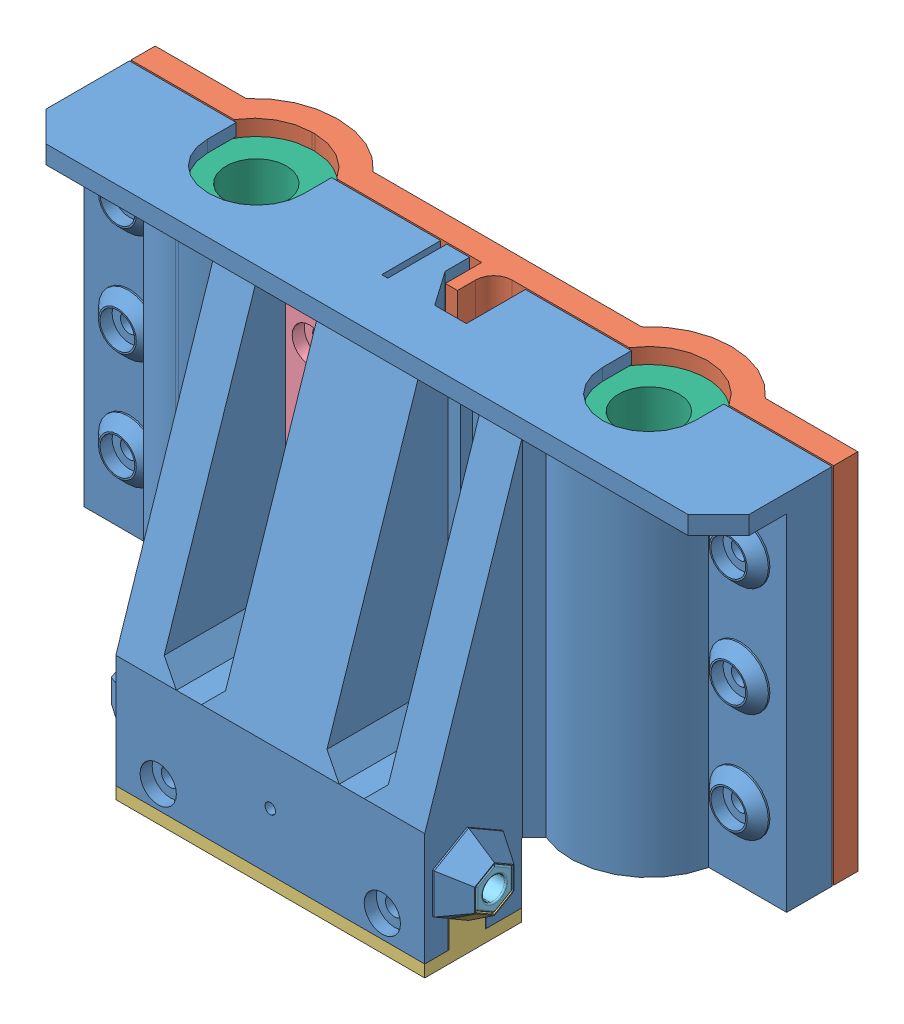
SolidWorks assembly axis-carriage-assembly, configuration Default. Lengths in mm.
Overall size (116 72 45.5).
7 component instances, 6 part files, 21 mates.
Components (placement in the parent):
- carriage-front-lm10luu-1: carriage-front-lm10luu [Default] at (0 -60 25) size (116 70 34.75)
- carriage-back-lm10luu-1: carriage-back-lm10luu [Default] at (0 -60 25) size (116 60 16.5)
- standoff-cover-lm10luu-1: standoff-cover-lm10luu [Default] at (0 -60 25) size (60 9.59 16)
- belt-wedge-lm10luu-1: belt-wedge-lm10luu [Default] at (0 -60 25) size (9.85 57 8.25)
- standoff-60mm-1: standoff-60mm [Default] at (0 -60.5215 47.975) x (0 -1 0) z (0 0 1) size (6.85 60 6)
- Bearing-linear-LM10LUU-1: Bearing-linear-LM10LUU [Default] at (32.5 -30 25) size (19 55 19)
- Bearing-linear-LM10LUU-2: Bearing-linear-LM10LUU [Default] at (-32.4997 -30 24.8078) size (19 55 19)
Mates (geometry in assembly coordinates):
- Concentric1: concentric aligned: cylinder of carriage-front-lm10luu-1 through (32.5 -60 25) axis (0 1 0) radius 9.625; cylinder of carriage-back-lm10luu-1 through (32.5 -60 25) axis (0 1 0) radius 9.625
- Concentric2: concentric aligned: cylinder of carriage-front-lm10luu-1 through (50.3647 -48 55) axis (0 0 -1) radius 1.5; cylinder of carriage-back-lm10luu-1 through (50.3647 -48 39) axis (0 0 -1) radius 1.5
- Concentric3: concentric aligned: cylinder of carriage-front-lm10luu-1 through (50.3647 -12 55) axis (0 0 -1) radius 1.5; cylinder of carriage-back-lm10luu-1 through (50.3647 -12 39) axis (0 0 -1) radius 1.5
- Coincident1: coincident aligned: plane of carriage-front-lm10luu-1 through (0 -60 25) normal (1 0 0); plane of assembly through (0 0 0) normal (1 0 0)
- Distance1: distance = 25 mm aligned: plane of carriage-front-lm10luu-1 through (0 -60 25) normal (0 0 1); plane of assembly through (0 0 0) normal (0 0 1)
- Coincident4: coincident aligned: plane of carriage-front-lm10luu-1 through (-1.85 0 33.8907) normal (0 1 0); plane of assembly through (0 0 0) normal (0 1 0)
- Concentric4: concentric aligned: cylinder of carriage-front-lm10luu-1 through (18.5 -66.25 -5) axis (0 0 1) radius 1.5; cylinder of standoff-cover-lm10luu-1 through (18.5 -66.25 -5) axis (0 0 1) radius 1.5
- Concentric5: concentric aligned: cylinder of carriage-front-lm10luu-1 through (-18.5 -66.25 -5) axis (0 0 1) radius 1.5; cylinder of standoff-cover-lm10luu-1 through (-18.5 -66.25 -5) axis (0 0 1) radius 1.5
- Coincident6: coincident aligned: plane of carriage-front-lm10luu-1 through (-126.884 -51.3583 55) normal (0 0 1); plane of standoff-cover-lm10luu-1 through (44.1527 -70 55) normal (0 0 1)
- Concentric6: concentric aligned: cylinder of carriage-back-lm10luu-1 through (-50.4897 -48 39) axis (0 0 -1) radius 1.5; cylinder of carriage-front-lm10luu-1 through (-50.4897 -48 55) axis (0 0 -1) radius 1.5
- Concentric7: concentric aligned: cylinder of carriage-front-lm10luu-1 through (-14.5103 -12 55) axis (0 0 -1) radius 1.5; cylinder of belt-wedge-lm10luu-1 through (-14.5103 -12 55) axis (0 0 -1) radius 1.5
- Distance6: distance = 1.5 mm anti-aligned: plane of carriage-front-lm10luu-1 through (-58 40 24.25) normal (0 0 1); plane of belt-wedge-lm10luu-1 through (-58 40 25.75) normal (0 0 -1)
- Concentric8: concentric aligned: cylinder of carriage-front-lm10luu-1 through (32.5 -60 25) axis (0 1 0) radius 9.625; cylinder of Bearing-linear-LM10LUU-1 through (32.5 16.0446 25) axis (0 1 0) radius 9.5
- Coincident14: coincident: moEndPointRef_w of carriage-front-lm10luu-1; plane of Bearing-linear-LM10LUU-1 through (32.5 -30 25) normal (0 1 0)
- Coincident15: coincident aligned: plane of Bearing-linear-LM10LUU-1 through (32.5 -30 25) normal (0 1 0); plane of Bearing-linear-LM10LUU-2 through (-32.4997 -30 24.8078) normal (0 1 0)
- Parallel1: parallel aligned: plane of Bearing-linear-LM10LUU-1 through (32.5 -30 25) normal (1 0 0); plane of Bearing-linear-LM10LUU-2 through (-32.4997 -30 24.8078) normal (1 0 0)
- Parallel2: parallel aligned: plane of Bearing-linear-LM10LUU-1 through (32.5 -30 25) normal (1 0 0); plane of assembly through (0 0 0) normal (1 0 0)
- Distance5: distance = 55 mm: cylinder of Bearing-linear-LM10LUU-1 through (32.5 16.0446 25) axis (0 1 0) radius 5; cylinder of Bearing-linear-LM10LUU-2 through (-32.4997 16.0446 24.8078) axis (0 1 0) radius 5
- Coincident16: coincident aligned: plane of carriage-front-lm10luu-1 through (-30 -60 25) normal (-1 0 0); plane of standoff-60mm-1 through (-30 -60.5215 47.975) normal (-1 0 0)
- Distance7: distance = 0.1 mm anti-aligned: plane of standoff-60mm-1 through (30 -62.2535 44.975) normal (0 0 -1); plane of carriage-front-lm10luu-1 through (-30 -62.3401 44.875) normal (0 0 1)
- Distance8: distance = 0.1 mm anti-aligned: plane of standoff-60mm-1 through (30 -58.7894 44.975) normal (0 0.866025 -0.5); plane of carriage-front-lm10luu-1 through (-30 -58.7317 44.875) normal (0 -0.866025 0.5)
